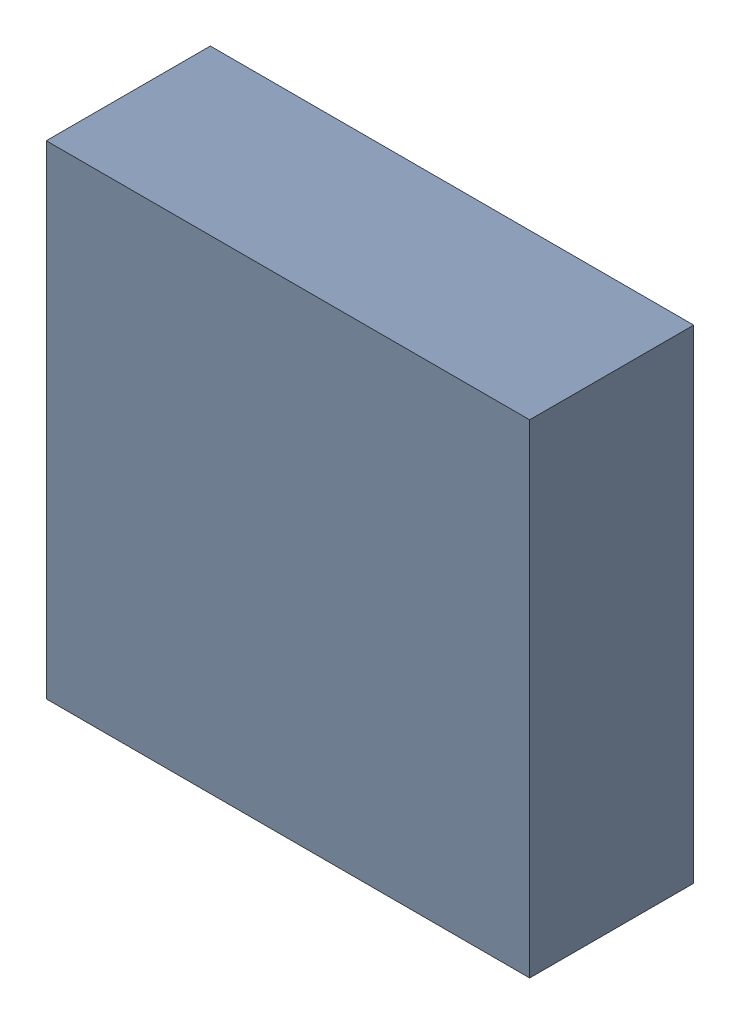
SolidWorks assembly U26, configuration ﾃﾞﾌｫﾙﾄ. Lengths in mm.
Overall size (3.3 3.3 1.12).
2 component instances, 1 part files, 0 mates.
Components (placement in the parent):
- 689263008-1: 689263008 [ﾃﾞﾌｫﾙﾄ] at (23 57.25 0) size (3.3 3.3 1.12)
  - Extruded_44-1: Extruded_44 [ﾃﾞﾌｫﾙﾄ] at origin size (3.3 3.3 1.12)
